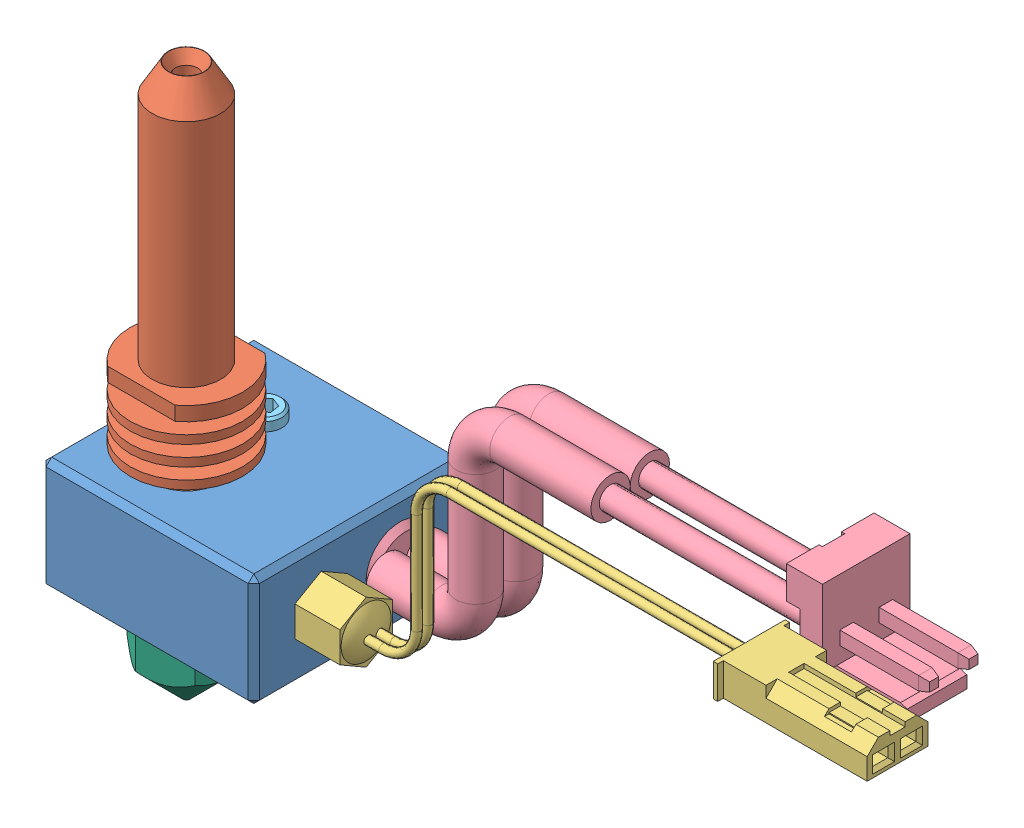
SolidWorks assembly SubEnsamblaje HotEnd BQ V1, configuration Predeterminado. Lengths in mm.
Overall size (70.79 49 19).
7 component instances, 7 part files, 18 mates.
Components (placement in the parent):
- hotend-heater-block-main-2: hotend-heater-block-main [Predeterminado] at (-11.7834 -133.63 -4.0653) x (1 0 0) z (0 1 0) size (19 19 10)
- Hotend-main-tube-final-1: Hotend-main-tube-final [Predeterminado] at (-11.7834 -133.63 -4.0653) x (1 0 0) z (0 1 0) size (10 10 36)
- hotend-thermistor-final-1: hotend-thermistor-final [Predeterminado] at (-11.7834 -133.63 -4.0653) x (1 0 0) z (0 1 0) size (55.29 6.4 19.1)
- hotend-heater-cartridge-1: hotend-heater-cartridge [Predeterminado] at (-11.7834 -133.63 -4.0653) x (1 0 0) z (0 1 0) size (68.81 7.8 23.9)
- extruder-setscrew2-1: extruder-setscrew2 [Predeterminado] at (-17.1285 -133.63 -2.6635) x (0.849368 0 -0.527801) z (0 1 0) size (3 3 3)
- hot-end-nozzle-final-1: hot-end-nozzle-final [Predeterminado] at (3.84 -133.63 6.6468) x (0.384008 0 0.92333) z (0 1 0) size (7 8.88 13)
- extruder-ptfe-tube-final-1: extruder-ptfe-tube-final [Predeterminado] at (-11.7834 175.08 30.0653) x (1 0 0) z (0 -1 0) size (4 4 25.2)
Mates (geometry in assembly coordinates):
- Coincidente3: coincident: plane of hotend-heater-block-main-2 through (-19 0 0) normal (0 -1 0); plane of assembly through (0 0 0) normal (0 1 0)
- Coincidente5: coincident: plane of hotend-heater-block-main-2 through (-19 0 0) normal (0 0 -1); plane of assembly through (0 0 0) normal (0 0 1)
- Coincidente6: coincident aligned: plane of hotend-heater-block-main-2 through (0 0 0) normal (1 0 0); plane of assembly through (0 0 0) normal (1 0 0)
- Paralelo2: parallel anti-aligned: plane of hotend-heater-block-main-2 through (-19 0 0) normal (0 -1 0); plane of hotend-thermistor-final-1 through (44.6003 21.4007 12.9966) normal (0 1 0)
- Concéntrica2: concentric aligned: cylinder of hotend-heater-block-main-2 through (0 5 13) axis (1 0 0) radius 1.23; cylinder of hotend-thermistor-final-1 through (-0.5 5 13) axis (1 0 0) radius 1.5
- Coincidente9: coincident anti-aligned: plane of hotend-heater-block-main-2 through (0 0 0) normal (1 0 0); plane of hotend-thermistor-final-1 through (0 7.702 13) normal (-1 0 0)
- Concéntrica7: concentric aligned: cylinder of hotend-heater-block-main-2 through (-19 5 6) axis (-1 0 0) radius 3; cylinder of hotend-heater-cartridge-1 through (0.5 5 6) axis (-1 0 0) radius 3
- Paralelo5: parallel aligned: plane of hotend-heater-block-main-2 through (-19 10 0) normal (0 1 0); plane of hotend-heater-cartridge-1 through (38.3135 25.9 2.1) normal (0 1 0)
- Coincidente12: coincident anti-aligned: plane of hotend-heater-block-main-2 through (0 0 0) normal (1 0 0); circle of hotend-heater-cartridge-1
- Bloquear2: lock: unknown of hotend-heater-block-main-2; unknown of extruder-setscrew2-1
- Tangente1: tangent anti-aligned: cylinder of hotend-heater-cartridge-1 through (0.5 5 6) axis (-1 0 0) radius 3; plane of extruder-setscrew2-1 through (-12 8 6) normal (0 -1 0)
- Bloquear3: lock: unknown of hotend-heater-block-main-2; unknown of Hotend-main-tube-final-1
- Concéntrica10: concentric: cylinder of hotend-heater-block-main-2 through (-12 10 13) axis (0 1 0) radius 2.46; cylinder of Hotend-main-tube-final-1 through (-12 10 13) axis (0 -1 0) radius 3
- Coincidente14: coincident: plane of hotend-heater-block-main-2 through (-19 10 0) normal (0 1 0); circle of Hotend-main-tube-final-1
- Bloquear4: lock: unknown of hotend-heater-block-main-2; unknown of hot-end-nozzle-final-1
- Coincidente15: coincident: plane of hotend-heater-block-main-2 through (-19 0 0) normal (0 -1 0); plane of hot-end-nozzle-final-1 through (-12 0 13) normal (0 1 0)
- Bloquear5: lock: unknown of Hotend-main-tube-final-1; unknown of extruder-ptfe-tube-final-1
- Coincidente16: coincident: plane of Hotend-main-tube-final-1 through (-12 5 13) normal (0 -1 0); circle of extruder-ptfe-tube-final-1
